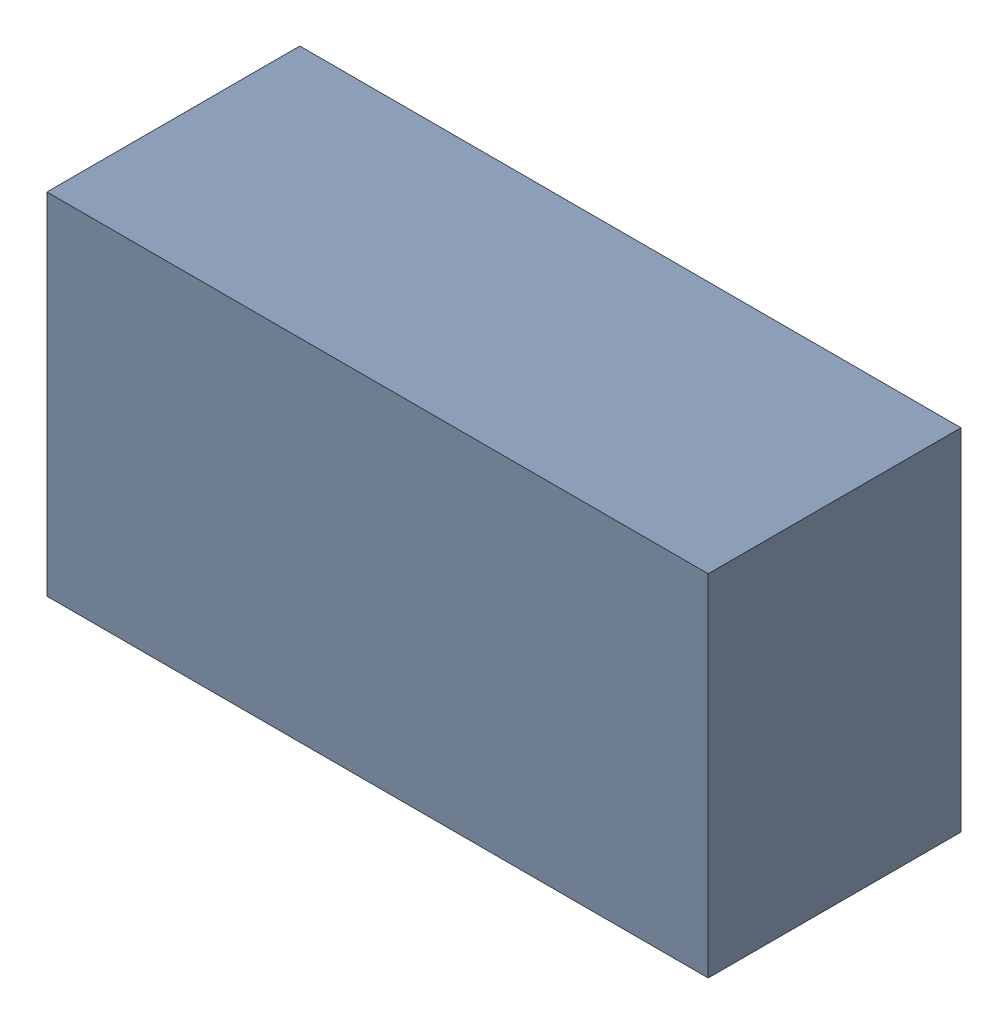
SolidWorks assembly C207, configuration Standard. Lengths in mm.
Overall size (3.4 1.8 1.3).
2 component instances, 1 part files, 0 mates.
Components (placement in the parent):
- 885542104-1: 885542104 [Standard] at (10.45 -22.95 0) size (3.4 1.8 1.3)
  - Extruded_29-1: Extruded_29 [Standard] at origin size (3.4 1.8 1.3)
